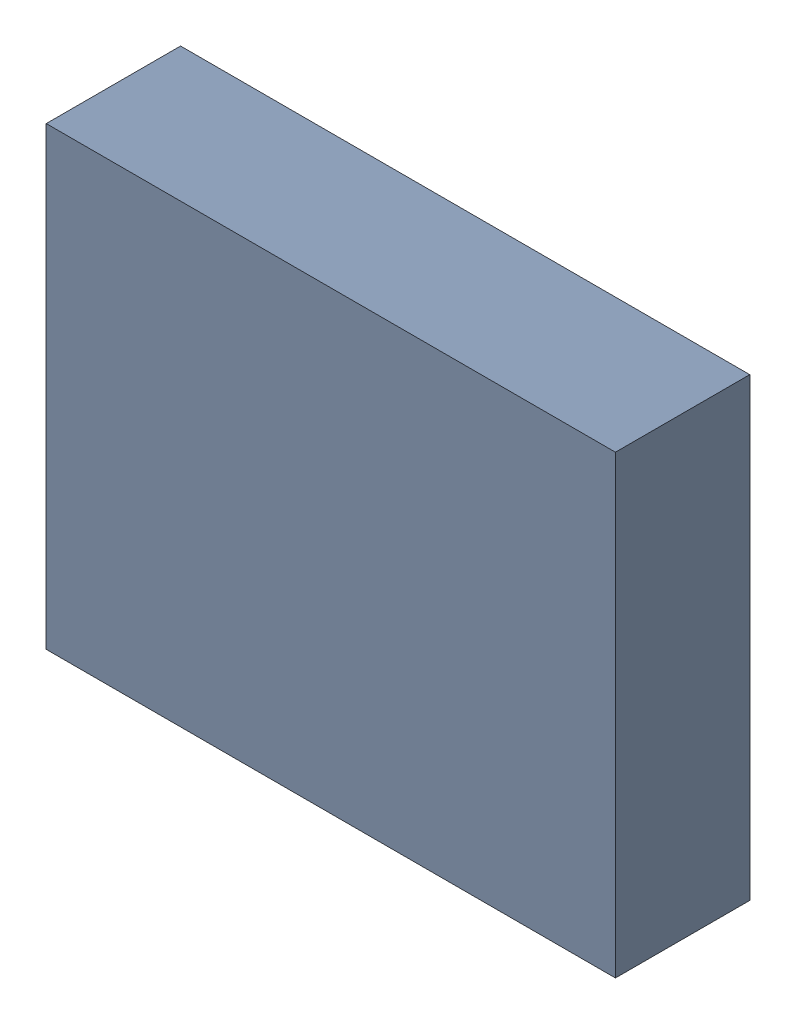
SolidWorks assembly L4, configuration Default. Lengths in mm.
Overall size (1.25 1 0.29).
2 component instances, 1 part files, 0 mates.
Components (placement in the parent):
- 870944000-1: 870944000 [Default] at (71.7542 41.5776 0.005) size (1.25 1 0.29)
  - Extruded_27-1: Extruded_27 [Default] at origin size (1.25 1 0.29)
